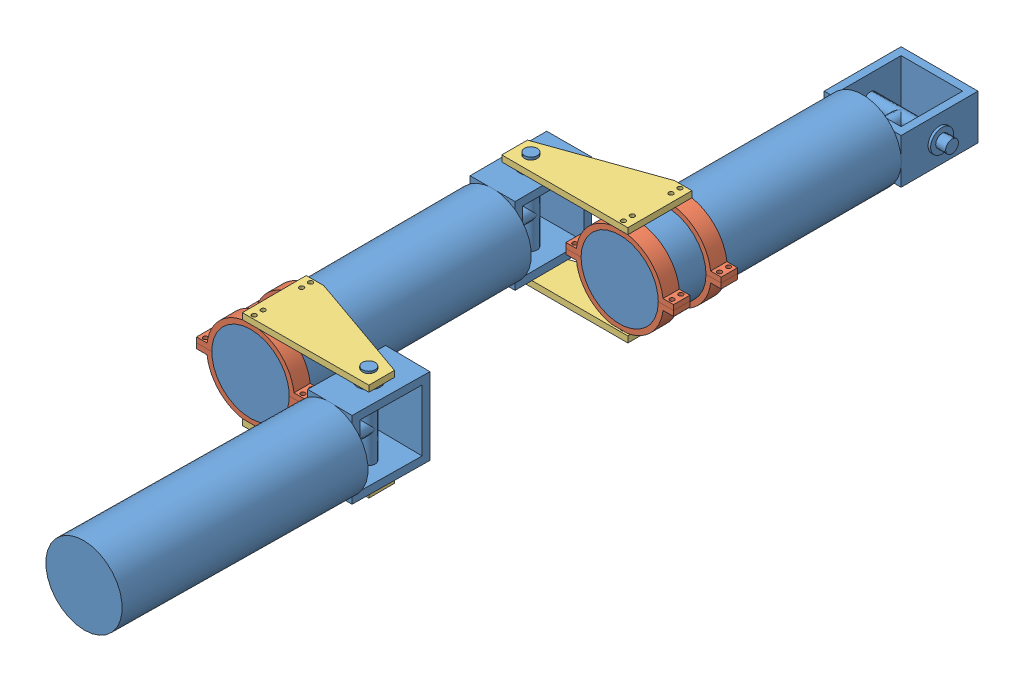
SolidWorks assembly EnsamblajeBrazo, configuration Predeterminado. Lengths in mm.
Overall size (164.02 79.9 665.85).
15 component instances, 3 part files, 38 mates.
Components (placement in the parent):
- EslabonSimplificado-1: EslabonSimplificado [Predeterminado] at origin size (79.5 60.33 249.5)
- EslabonSimplificado-2: EslabonSimplificado [Predeterminado] at (-80.65 0.4018 208.15) x (0 1 0) z (0.003708 0 0.999993) size (79.5 60.33 249.5)
- SujeccionMotor-1: SujeccionMotor [Predeterminado] at (0 0 206.8) x (0 -1 0) z (0 0 1) size (33.4 84 12.7)
- SujeccionMotor-2: SujeccionMotor [Predeterminado] at (0 0 206.8) x (0 1 0) z (0 0 1) size (33.4 84 12.7)
- SujeccionMotor-3: SujeccionMotor [Predeterminado] at (0 0 169.65) x (0 -1 0) z (0 0 1) size (33.4 84 12.7)
- SujeccionMotor-4: SujeccionMotor [Predeterminado] at (0 0 182.35) x (0 1 0) z (0 0 -1) size (33.4 84 12.7)
- Soporte-1: Soporte [Predeterminado] at (6.35 33.4018 219.5) x (0 0 1) z (0 1 0) size (50 98.35 4.76)
- Soporte-2: Soporte [Predeterminado] at (6.35 -39.7518 219.5) x (0 0 1) z (0 1 0) size (50 98.35 4.76)
- SujeccionMotor-5: SujeccionMotor [Predeterminado] at (-79.836 0.4018 427.6485) x (0 -1 0) z (-0.003708 0 -0.999993) size (33.4 84 12.7)
- SujeccionMotor-6: SujeccionMotor [Predeterminado] at (-79.9738 0.4018 390.4987) x (0 -1 0) z (-0.003708 0 -0.999993) size (33.4 84 12.7)
- SujeccionMotor-7: SujeccionMotor [Predeterminado] at (-79.9738 0.4018 390.4987) x (0 1 0) z (-0.003708 0 -0.999993) size (33.4 84 12.7)
- SujeccionMotor-8: SujeccionMotor [Predeterminado] at (-79.836 0.4018 427.6485) x (0 1 0) z (-0.003708 0 -0.999993) size (33.4 84 12.7)
- Soporte-3: Soporte [Predeterminado] at (-86.186 38.566 427.672) x (0.003708 0 0.999993) z (0 -1 0) size (50 98.35 4.76)
- Soporte-4: Soporte [Predeterminado] at (-86.186 -33 427.672) x (0.003708 0 0.999993) z (0 -1 0) size (50 98.35 4.76)
- EslabonSimplificado-3: EslabonSimplificado [Predeterminado] at (0.7713 0.4018 415.9995) x (0 1 0) z (-0.012309 0 0.999924) size (79.5 60.33 249.5)
Mates (geometry in assembly coordinates):
- Concéntrica1: concentric anti-aligned: cylinder of EslabonSimplificado-1 through (0 0 30) axis (0 0 1) radius 30.165; cylinder of SujeccionMotor-2 through (0 0 219.5) axis (0 0 -1) radius 30
- Concéntrica2: concentric anti-aligned: cylinder of EslabonSimplificado-1 through (0 0 30) axis (0 0 1) radius 30.165; cylinder of SujeccionMotor-1 through (0 0 219.5) axis (0 0 -1) radius 30
- Paralelo2: parallel aligned: plane of EslabonSimplificado-1 through (0 17.5 0) normal (0 1 0); plane of SujeccionMotor-1 through (0 33.4018 219.5) normal (0 1 0)
- Coincidente1: coincident aligned: plane of SujeccionMotor-1 through (0 0 219.5) normal (0 0 1); plane of SujeccionMotor-2 through (0 0 219.5) normal (0 0 1)
- Coincidente2: coincident anti-aligned: plane of SujeccionMotor-1 through (0 0 219.5) normal (0 -1 0); plane of SujeccionMotor-2 through (0 0 219.5) normal (0 1 0)
- Concéntrica4: concentric aligned: cylinder of EslabonSimplificado-1 through (0 0 30) axis (0 0 1) radius 30.165; cylinder of SujeccionMotor-4 through (0 0 169.65) axis (0 0 1) radius 30
- Concéntrica5: concentric anti-aligned: cylinder of EslabonSimplificado-1 through (0 0 30) axis (0 0 1) radius 30.165; cylinder of SujeccionMotor-3 through (0 0 182.35) axis (0 0 -1) radius 30
- Coincidente3: coincident aligned: plane of SujeccionMotor-1 through (0 4 219.5) normal (0 1 0); plane of SujeccionMotor-3 through (0 4 182.35) normal (0 1 0)
- Coincidente4: coincident anti-aligned: plane of SujeccionMotor-3 through (0 0 182.35) normal (0 -1 0); plane of SujeccionMotor-4 through (0 0 169.65) normal (0 1 0)
- Coincidente5: coincident aligned: plane of SujeccionMotor-3 through (0 0 182.35) normal (0 0 1); plane of SujeccionMotor-4 through (0 0 182.35) normal (0 0 1)
- Coincidente6: coincident aligned: plane of EslabonSimplificado-1 through (0 0 219.5) normal (0 0 1); plane of SujeccionMotor-2 through (0 0 219.5) normal (0 0 1)
- Concéntrica6: concentric anti-aligned: cylinder of SujeccionMotor-1 through (0 -0.001 216.65) axis (0 1 0) radius 1.75; cylinder of Soporte-1 through (0 38.1643 216.65) axis (0 -1 0) radius 1.75
- Coincidente7: coincident anti-aligned: plane of SujeccionMotor-1 through (0 33.4018 219.5) normal (0 1 0); plane of Soporte-1 through (6.35 33.4018 219.5) normal (0 -1 0)
- Concéntrica7: concentric anti-aligned: cylinder of SujeccionMotor-3 through (0 -0.001 172.5) axis (0 1 0) radius 1.75; cylinder of Soporte-1 through (0 38.1643 172.5) axis (0 -1 0) radius 1.75
- Concéntrica8: concentric anti-aligned: cylinder of EslabonSimplificado-2 through (-80.65 -62.5982 208.15) axis (0 1 0) radius 5; cylinder of Soporte-1 through (-80.65 38.1643 208.15) axis (0 -1 0) radius 5
- Concéntrica9: concentric aligned: cylinder of SujeccionMotor-2 through (0 0.001 209.65) axis (0 -1 0) radius 1.75; cylinder of Soporte-2 through (0 -34.9893 209.65) axis (0 -1 0) radius 1.75
- Concéntrica10: concentric aligned: cylinder of SujeccionMotor-4 through (0 0.001 172.5) axis (0 -1 0) radius 1.75; cylinder of Soporte-2 through (0 -34.9893 172.5) axis (0 -1 0) radius 1.75
- Distancia1: distance = 1 mm anti-aligned: plane of EslabonSimplificado-2 through (-80.65 32.4018 208.15) normal (0 1 0); plane of Soporte-1 through (6.35 33.4018 219.5) normal (0 -1 0)
- Concéntrica111: concentric aligned: cylinder of EslabonSimplificado-2 through (-80.5388 0.4018 238.1498) axis (0.003708 0 0.999993) radius 30.165; cylinder of SujeccionMotor-5 through (-79.8831 0.4018 414.9486) axis (0.003708 0 0.999993) radius 34
- Concéntrica121: concentric aligned: cylinder of EslabonSimplificado-2 through (-80.5388 0.4018 238.1498) axis (0.003708 0 0.999993) radius 30.165; cylinder of SujeccionMotor-6 through (-80.0209 0.4018 377.7988) axis (0.003708 0 0.999993) radius 34
- Concéntrica131: concentric aligned: cylinder of EslabonSimplificado-2 through (-80.5388 0.4018 238.1498) axis (0.003708 0 0.999993) radius 30.165; cylinder of SujeccionMotor-7 through (-80.0209 0.4018 377.7988) axis (0.003708 0 0.999993) radius 34
- Concéntrica141: concentric aligned: cylinder of EslabonSimplificado-2 through (-80.5388 0.4018 238.1498) axis (0.003708 0 0.999993) radius 30.165; cylinder of SujeccionMotor-8 through (-79.8831 0.4018 414.9486) axis (0.003708 0 0.999993) radius 34
- Paralelo3: parallel aligned: plane of EslabonSimplificado-2 through (-63.2614 30.4018 178.0853) normal (0 1 0); plane of SujeccionMotor-5 through (-79.8831 4.4018 414.9486) normal (0 1 0)
- Coincidente8: coincident aligned: plane of EslabonSimplificado-2 through (-79.836 0.4018 427.6485) normal (0.003708 0 0.999993); plane of SujeccionMotor-5 through (-79.836 0.4018 427.6485) normal (0.003708 0 0.999993)
- Coincidente9: coincident anti-aligned: plane of SujeccionMotor-5 through (-79.8831 0.4018 414.9486) normal (0 -1 0); plane of SujeccionMotor-8 through (-79.8831 0.4018 414.9486) normal (0 1 0)
- Coincidente10: coincident aligned: plane of SujeccionMotor-5 through (-79.836 0.4018 427.6485) normal (0.003708 0 0.999993); plane of SujeccionMotor-8 through (-79.836 0.4018 427.6485) normal (0.003708 0 0.999993)
- Coincidente11: coincident aligned: plane of SujeccionMotor-6 through (-79.9738 0.4018 390.4987) normal (0.003708 0 0.999993); plane of SujeccionMotor-7 through (-79.9738 0.4018 390.4987) normal (0.003708 0 0.999993)
- Coincidente12: coincident anti-aligned: plane of SujeccionMotor-6 through (-80.0209 0.4018 377.7988) normal (0 -1 0); plane of SujeccionMotor-7 through (-80.0209 0.4018 377.7988) normal (0 1 0)
- Paralelo4: parallel aligned: plane of SujeccionMotor-5 through (-79.8831 4.4018 414.9486) normal (0 1 0); plane of SujeccionMotor-6 through (-80.0209 4.4018 377.7988) normal (0 1 0)
- Concéntrica142: concentric aligned: cylinder of SujeccionMotor-5 through (-79.8466 0.4008 424.7985) axis (0 1 0) radius 1.75; cylinder of Soporte-3 through (-79.8466 33.8035 424.7985) axis (0 1 0) radius 1.75
- Concéntrica143: concentric aligned: cylinder of SujeccionMotor-6 through (-79.9844 0.4008 387.6488) axis (0 1 0) radius 1.75; cylinder of Soporte-3 through (-79.9844 33.8035 387.6488) axis (0 1 0) radius 1.75
- Coincidente13: coincident anti-aligned: plane of SujeccionMotor-5 through (-79.8831 33.8035 414.9486) normal (0 1 0); plane of Soporte-3 through (-86.186 33.8035 427.672) normal (0 -1 0)
- Concéntrica144: concentric anti-aligned: cylinder of SujeccionMotor-8 through (-79.8725 0.4028 417.7986) axis (0 -1 0) radius 1.75; cylinder of Soporte-4 through (-79.8725 -37.7625 417.7986) axis (0 1 0) radius 1.75
- Concéntrica145: concentric anti-aligned: cylinder of SujeccionMotor-7 through (-80.0103 0.4028 380.6488) axis (0 -1 0) radius 1.75; cylinder of Soporte-4 through (-80.0103 -37.7625 380.6488) axis (0 1 0) radius 1.75
- Coincidente14: coincident anti-aligned: plane of SujeccionMotor-8 through (-79.8831 -33 414.9486) normal (0 -1 0); plane of Soporte-4 through (-86.186 -33 427.672) normal (0 1 0)
- Concéntrica146: concentric aligned: cylinder of Soporte-3 through (0.7713 33.8035 415.9995) axis (0 1 0) radius 5; cylinder of EslabonSimplificado-3 through (0.7713 -62.5982 415.9995) axis (0 1 0) radius 5
- Paralelo5: parallel aligned: plane of EslabonSimplificado-2 through (-63.2614 -29.5982 178.0853) normal (0 -1 0); plane of EslabonSimplificado-3 through (18.6393 -29.5982 386.2172) normal (0 -1 0)
- Coincidente15: coincident aligned: plane of EslabonSimplificado-2 through (-63.2614 30.4018 178.0853) normal (0 1 0); plane of EslabonSimplificado-3 through (18.6393 30.4018 386.2172) normal (0 1 0)
